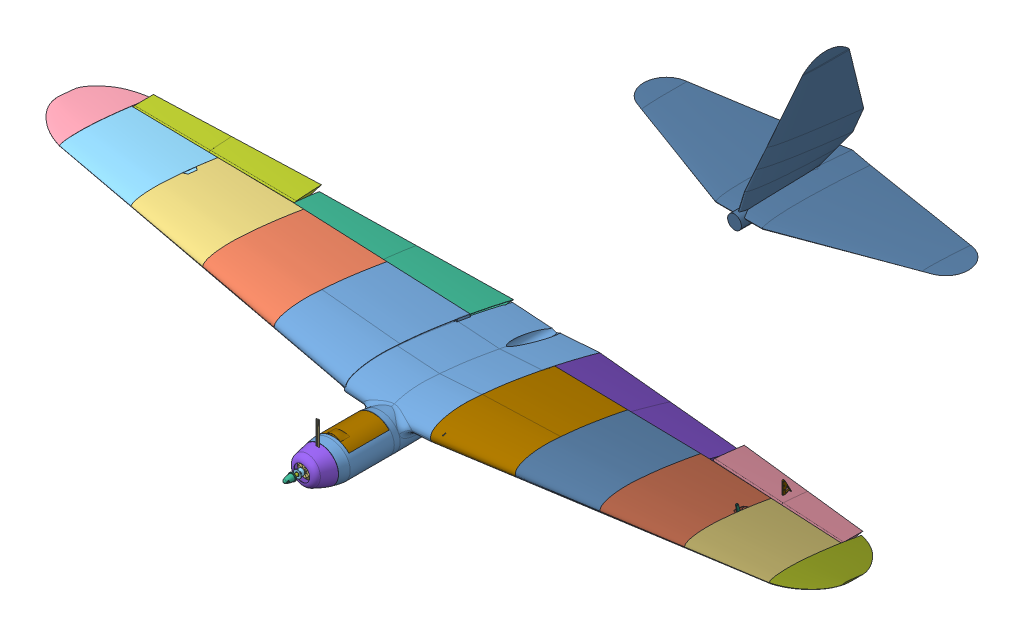
SolidWorks assembly assemtest2, configuration Default. Lengths in mm.
Overall size (1260.45 264.35 1066.65).
30 component instances, 28 part files, 14 mates.
Components (placement in the parent):
- fuselage_4-1: fuselage_4 [Default] at (-47.2556 -45.7462 449.1131) size (516.5 263.99 1037.62)
- Turnigy_2200mAh_3S_20C_Lipo_Pack-1: Turnigy_2200mAh_3S_20C_Lipo_Pack [Valor predeterminado] at (-47.4974 -36.5844 408.8906) x (0 0 1) z (0 -1 0) size (103 34 24)
- BLDC_A2212_13T_1000KV_Assemly-1: BLDC_A2212_13T_1000KV_Assemly [Default] at (-47.2556 -31.5075 542.6563) x (-0.001566 0.999999 0) z (0.999999 0.001566 0) size (87.69 59.44 56.76)
  - BLDC_A2212_13T_1000KV-1: BLDC_A2212_13T_1000KV [Default] at origin size (73.15 40.13 27.69)
  - BLDC_A2212_13T_1000KV_MountPlate-1: BLDC_A2212_13T_1000KV_MountPlate [Default] at (0 -26.67 0) x (-0.707107 0 -0.707107) z (-0.707107 0 0.707107) size (40.13 1.47 40.13)
  - BLDC_A2212_13T_1000KV_PropCollar-1: BLDC_A2212_13T_1000KV_PropCollar [Default] at (0 8.8646 0) x (0.997679 0 0.068095) z (0.068095 0 -0.997679) size (12.06 6.96 12.06)
  - BLDC_A2212_13T_1000KV_PropNut-1: BLDC_A2212_13T_1000KV_PropNut [Default] at (0 16.0097 0) x (-0.117252 0 0.993102) z (-0.993102 0 -0.117252) size (11.84 14.81 11.84)
  - BLDC_A2212_13T_1000KV_PropThread-1: BLDC_A2212_13T_1000KV_PropThread [Default] at (0 1.905 0) size (7.91 22.53 7.91)
- nosecone-1: nosecone [Default] at (-47.4088 -46.1222 449.1131) size (60.54 59.23 32.07)
- Left Wing Assembly version 3.0-1: Left Wing Assembly version 3.0 [Default] at (39.3976 -129.7812 195.3519) x (0.999505 -0.031395 0.001764) z (-0.001217 0.01741 0.999848) size (1257.86 91.52 276.09)
  - holes_sec1-1: holes_sec1 [Default] at (-21.1787 103.8047 214.3011) size (139.88 62.18 205.01)
  - holes_sec2-1: holes_sec2 [Default] at (-21.1787 103.8047 214.3011) size (142.86 54.4 187.37)
  - holes_sec3-1: holes_sec3 [Default] at (-21.1787 103.8047 214.3011) size (141.4 44.82 168.18)
  - holes_sec4-1: holes_sec4 [Default] at (-21.1787 103.8047 214.3011) size (133.72 34.85 144.08)
  - wang_fin2_aileron_left-1: wang_fin2_aileron_left [Default] at (-19.3474 67.6819 204.2839) x (0.999776 0.020626 -0.004663) z (0.008001 -0.164862 0.986284) size (232.68 32.44 70.02)
  - Servo Motor (SG90)-1: Servo Motor (SG90) [Default] at (369.0001 141.0439 92.2244) x (0.123302 -0.062035 -0.990428) z (0.987706 0.104311 0.11643) size (31.9 11.8 29.9)
  - Servo Control Rod-1: Servo Control Rod [Default] at (349.0307 139.3365 95.247) x (0.094489 0.19497 -0.976247) z (0.987706 0.104311 0.11643) size (5 20 3)
  - wangtip-2: wangtip [Default] at (479.0832 126.5551 183.6971) x (0.994881 0.101056 0) z (-0.003437 0.03384 0.999421) size (72.69 16.61 151.1)
  - wang_fin2_trailingedge-2: wang_fin2_trailingedge [Default] at (-21.1787 103.8047 214.3011) size (279.36 44.38 89.85)
  - Aileron_Hook_left-1: Aileron_Hook_left [Default] at (355.9995 137.0895 25.4434) x (-0.060242 0.132243 0.989385) z (-0.992737 -0.111338 -0.045564) size (16.5 21.5 15)
  - holes_sec1Mirror-2: holes_sec1Mirror [Default] at (-156.6987 103.8047 214.3011) x (-1 0 0) z (0 0 -1) size (139.88 62.18 205.01)
  - holes_sec2Mirror-2: holes_sec2Mirror [Default] at (-156.6987 103.8047 214.3011) x (-1 0 0) z (0 0 -1) size (142.86 54.4 187.37)
  - holes_sec3Mirror-2: holes_sec3Mirror [Default] at (-156.6987 103.8047 214.3011) x (-1 0 0) z (0 0 -1) size (141.4 44.82 168.18)
  - wangtipMirror-3: wangtipMirror [Default] at (-656.9606 126.5551 183.6971) x (-0.994881 0.101056 0) z (-0.003437 -0.03384 -0.999421) size (72.69 16.61 151.1)
  - holes_sec4Mirror-2: holes_sec4Mirror [Default] at (-156.6987 103.8047 214.3011) x (-1 0 0) z (0 0 -1) size (133.72 34.85 144.08)
  - wang_fin2_trailingedgeMirror-3: wang_fin2_trailingedgeMirror [Default] at (-156.6987 103.8047 214.3011) x (-1 0 0) z (0 0 -1) size (279.36 44.38 89.85)
  - wang_fin2_aileron_leftMirror-2: wang_fin2_aileron_leftMirror [Default] at (-158.53 67.6819 204.2839) x (-0.999776 0.020626 -0.004663) z (0.008001 0.164862 -0.986284) size (232.68 32.44 70.02)
- motor mountingplate-1: motor mountingplate [Default] at (-47.2556 -31.5075 515.1131) x (-0.999586 -0.028789 0) z (0 0 -1) size (45 42.1 3)
- nose_cover-1: nose_cover [Default] at (-47.2556 -45.7462 494.2516) x (-1 0 0) z (0 0 -1) size (49.79 14.73 65.15)
- tail-1: tail [Default] at (-47.2556 -46.1081 436.3731) size (516.5 263.99 880.47)
Mates (geometry in assembly coordinates):
- Coincident1: coincident anti-aligned: plane of fuselage_4-1 through (-84.0444 -66.8474 460.3906) normal (0 0 -1); plane of Turnigy_2200mAh_3S_20C_Lipo_Pack-1 through (-64.4974 -60.5844 460.3906) normal (0 0 1)
- Parallel1: parallel aligned: plane of Turnigy_2200mAh_3S_20C_Lipo_Pack-1 through (-47.4974 -36.5844 408.8906) normal (0 1 0)
- Concentric1: concentric aligned: line of fuselage_4-1 through (-47.2556 -31.5075 519.0909) axis (0 0 -1); cylinder of BLDC_A2212_13T_1000KV_Assemly-1/BLDC_A2212_13T_1000KV-1 through (-47.2556 -31.5075 513.7003) axis (0 0 -1) radius 13.843
- Coincident6: coincident anti-aligned: plane of fuselage_4-1 through (-47.2556 -45.7462 514.1131) normal (0 0 1); plane of nosecone-1 through (-47.4088 -46.1222 514.1131) normal (0 0 -1)
- Parallel2: parallel anti-aligned: plane of fuselage_4-1 through (20.2083 -7.0335 277.0273) normal (0.997564 0.069756 0); plane of Left Wing Assembly version 3.0-1/holes_sec1-1 through (22.727 -43.0531 275.9747) normal (-0.997564 -0.069756 0)
- Coincident8: coincident: point of fuselage_4-1; point of Left Wing Assembly version 3.0-1/holes_sec1-1
- Coincident9: coincident: point of fuselage_4-1; point of Left Wing Assembly version 3.0-1/wang_fin2_trailingedge-2
- Concentric2: concentric aligned: cylinder of fuselage_4-1 through (-47.2556 -31.5075 131.3824) axis (0 0 1) radius 21; cylinder of motor mountingplate-1 through (-47.2556 -31.5075 513.1131) axis (0 0 1) radius 21
- Distance1: distance = 0.6 mm: plane of BLDC_A2212_13T_1000KV_Assemly-1/BLDC_A2212_13T_1000KV_MountPlate-1 through (-35.7791 -19.8152 514.5131) normal (0 0 -1); plane of motor mountingplate-1 through (-47.2556 -31.5075 515.1131) normal (0 0 1)
- Coincident15: coincident: circle of fuselage_4-1; circle of motor mountingplate-1
- Parallel4: parallel anti-aligned: plane of fuselage_4-1 through (-47.2556 -45.7462 494.1131) normal (0 0 -1); plane of nose_cover-1 through (-47.4092 -37.0918 494.2516) normal (0 0 1)
- Coincident17: coincident anti-aligned: line of fuselage_4-1 through (-22.5163 -19.03 494.1131) axis (0 0 -1); line of nose_cover-1 through (-22.5163 -19.03 430.2516) axis (0 0 1)
- Coincident18: coincident anti-aligned: plane of fuselage_4-1 through (-86.6909 -19.03 430.1131) normal (0 1 0); plane of nose_cover-1 through (-70.9337 -19.03 430.2516) normal (0 -1 0)
- Concentric3: concentric anti-aligned: cylinder of fuselage_4-1 through (-47.2556 -31.8695 639.1131) axis (0 0 -1) radius 10; circle of tail-1
